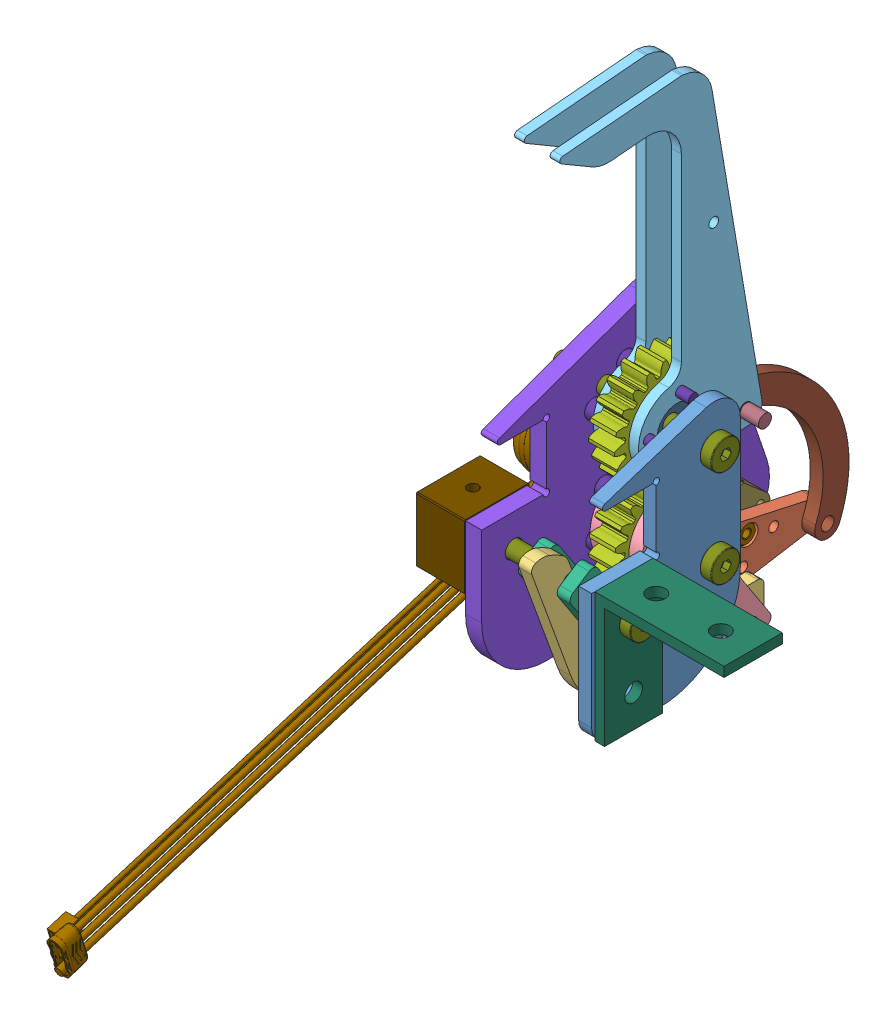
SolidWorks assembly 救援, configuration 默认. Lengths in mm.
Overall size (126.8 267.21 211.07).
35 component instances, 18 part files, 85 mates.
Components (placement in the parent):
- 微动开关固定板6666666-1: 微动开关固定板6666666 [镜像] x (0 0 1) z (0 1 0) size (46 4 73.5)
- 电机摇杆6666666-1: 电机摇杆6666666 [默认] at (-21.5 -25.5 -32) x (0 0.214023 0.976829) z (1 0 0) size (37.41 16.17 4)
- 钩子6666666-1: 钩子6666666 [默认] at (-16.5 -38.9961 -21.8634) x (0 0 -1) z (1 0 0) size (71.95 49.17 4)
- 弯抓6666666-1: 弯抓6666666 [默认] at (-10.5 -5.5 0) x (1 0 0) z (0 -0.837404 -0.546585) size (4 24 57)
- 下爪6666666-1: 下爪6666666 [默认] at (-10.5 24.5 0) x (1 0 0) z (0 0.994276 -0.106844) size (3 72.53 105)
- 摇杆6666666-1: 摇杆6666666 [默认] at (-22.5 -38.9961 6.1366) x (0 -0.837404 -0.546585) z (0 -0.546585 0.837404) size (50 4 10)
- 圆柱齿轮20×1.5-1: 圆柱齿轮20×1.5 [主动] at (-10.5 -5.5 0) x (0 -0.837404 -0.546585) z (-1 0 0) size (32.74 32.74 8)
- 电机固定板6666666-1: 电机固定板6666666 [默认] at (-35 -25.5 -32) x (0 0 1) z (1 0 0) size (89.04 83.8 5)
- RoboMaster M2006 P36直流无刷减速电机-1: RoboMaster M2006 P36直流无刷减速电机 [默认] at (-64.8952 -18.4138 -51.1986) x (0 -0.468644 -0.883387) z (-1 0 0) size (140.17 141.41 64.8)
- 圆柱齿轮20×1.5-3: 圆柱齿轮20×1.5 [从动] at (-10.5 24.5 0) x (0 0.994276 -0.106844) z (-1 0 0) size (32.74 32.74 8)
- 下爪6666666-2: 下爪6666666 [默认] at (-21.5 24.5 0) x (1 0 0) z (0 0.994276 -0.106844) size (3 72.53 105)
- 弯抓6666666-2: 弯抓6666666 [默认] at (-22.5 -5.5 0) x (1 0 0) z (0 -0.837404 -0.546585) size (4 24 57)
- 摇杆6666666-2: 摇杆6666666 [默认] at (-10.5 -38.9961 6.1366) x (0 -0.837404 -0.546585) z (0 -0.546585 0.837404) size (50 4 10)
- 法兰轴承-1: 法兰轴承 [5*11*4-1] at (-9.5 -5.5 0) x (0 -0.083503 0.996508) z (0 -0.996508 -0.083503) size (12.5 4 12.5)
- 法兰轴承-2: 法兰轴承 [5*11*4-1] at (-19.5 -5.5 0) x (0 0.17541 -0.984495) z (0 -0.984495 -0.17541) size (12.5 4 12.5)
- 救援连杆-1: 救援连杆 [默认] at (-14.5 -5.6678 -36.3434) x (0 -0.846057 -0.533093) z (1 0 0) size (65 22.68 4)
- 6mmD型孔联轴器-1: 6mmD型孔联轴器 [默认] at (-21.5 -25.5 -32) x (0 0.95603 0.293268) z (-1 0 0) size (19.05 22 8)
- 一字塞打螺丝-1: 一字塞打螺丝 [￠4*14M4*6] at (-23.5 18.4448 -21.1503) x (0 -0.238327 0.971185) z (-1 0 0) size (8 8 22)
- 法兰轴承-3: 法兰轴承 [5*11*4-1] at (-9.5 24.5 0) x (0 -0.183395 0.983039) z (0 -0.983039 -0.183395) size (12.5 4 12.5)
- 法兰轴承-4: 法兰轴承 [5*11*4-1] at (-19.5 24.5 0) x (0 0.545578 -0.83806) z (0 -0.83806 -0.545578) size (12.5 4 12.5)
- 赛钢轴套-1: 赛钢轴套 [默认] at (-11.5 18.4448 -21.1503) x (0 0.682052 -0.731304) z (1 0 0) size (8 8 2)
- 赛钢轴套-2: 赛钢轴套 [默认] at (-17.5 18.4448 -21.1503) x (0 0.813789 -0.58116) z (1 0 0) size (8 8 2)
- 角件6666666-1: 角件6666666 [默认] at (44 4.5 19) x (0 0 1) z (0 1 0) size (18 40 40)
- 304不锈钢塞打螺钉-1: 304不锈钢塞打螺钉 [5*40*M4] at (10.5 -5.5 28) x (-1 0 0) z (0 -0.996982 0.077638) size (51.5 9 9)
- 304不锈钢塞打螺钉-2: 304不锈钢塞打螺钉 [5*40*M4] at (7.5 24.5 0) x (-1 0 0) z (0 -0.996982 0.077638) size (51.5 9 9)
- 304不锈钢塞打螺钉-3: 304不锈钢塞打螺钉 [5*40*M4] at (7.5 -5.5 0) x (-1 0 0) z (0 -0.996982 0.077638) size (51.5 9 9)
- 12.9级圆柱头螺钉-1: 12.9级圆柱头螺钉 [M3*18] at (-24.5 23.5384 -8.9485) x (0 0.010518 0.999945) z (-1 0 0) size (5.68 5.68 21)
- 12.9级圆柱头螺钉-2: 12.9级圆柱头螺钉 [M3*18] at (-24.5 33.4485 -0.9616) x (0 0.010518 0.999945) z (-1 0 0) size (5.68 5.68 21)
- 12.9级圆柱头螺钉-3: 12.9级圆柱头螺钉 [M3*18] at (-24.5 25.4616 8.9485) x (0 0.010518 0.999945) z (-1 0 0) size (5.68 5.68 21)
- 12.9级圆柱头螺钉-4: 12.9级圆柱头螺钉 [M3*18] at (-24.5 15.5515 0.9616) x (0 0.010518 0.999945) z (-1 0 0) size (5.68 5.68 21)
- 12.9级圆柱头螺钉-5: 12.9级圆柱头螺钉 [M3*20] at (-25.5 -0.5807 -7.5366) x (0 0.010518 0.999945) z (-1 0 0) size (5.68 5.68 23)
- 12.9级圆柱头螺钉-6: 12.9级圆柱头螺钉 [M3*20] at (-25.5 2.0366 4.9193) x (0 0.010518 0.999945) z (-1 0 0) size (5.68 5.68 23)
- 12.9级圆柱头螺钉-7: 12.9级圆柱头螺钉 [M3*20] at (-25.5 -10.4193 7.5366) x (0 0.010518 0.999945) z (-1 0 0) size (5.68 5.68 23)
- 12.9级圆柱头螺钉-8: 12.9级圆柱头螺钉 [M3*20] at (-25.5 -13.0366 -4.9193) x (0 0.010518 0.999945) z (-1 0 0) size (5.68 5.68 23)
- 救援铝件-1: 救援铝件 [默认] at (-42.75 -5.5 28) x (0 0 -1) z (1 0 0) size (20 20 15.5)
Mates (geometry in assembly coordinates):
- 重合1: coincident aligned: plane of 微动开关固定板6666666-1 through (0 0 0) normal (0 1 0)
- 重合2: coincident aligned: plane of 微动开关固定板6666666-1 through (0 0 0) normal (1 0 0)
- 重合3: coincident aligned: plane of 微动开关固定板6666666-1 through (0 0 0) normal (0 0 1)
- 重合4: coincident aligned: plane of 微动开关固定板6666666-1 through (4 4.5 38) normal (0 1 0); plane of 电机固定板6666666-1 through (-30 4.5 18) normal (0 1 0)
- 重合5: coincident aligned: plane of 微动开关固定板6666666-1 through (4 4.5 18) normal (0 0 1); plane of 电机固定板6666666-1 through (-30 24.5 18) normal (0 0 1)
- 同心1: concentric anti-aligned: cylinder of 电机固定板6666666-1 through (-30 -25.5 -32) axis (-1 0 0) radius 7; cylinder of RoboMaster M2006 P36直流无刷减速电机-1 through (-18 -25.5 -32) axis (1 0 0) radius 12.2
- 重合11: coincident anti-aligned: plane of 电机固定板6666666-1 through (-35 -20.5 18) normal (-1 0 0); plane of RoboMaster M2006 P36直流无刷减速电机-1 through (-35 -21.9221 -43.6636) normal (1 0 0)
- 同心4: concentric aligned: cylinder of 微动开关固定板6666666-1 through (4 -5.5 0) axis (-1 0 0) radius 2.5; cylinder of 圆柱齿轮20×1.5-1 through (-10.5 -5.5 0) axis (-1 0 0) radius 5.5
- 重合12: coincident aligned: plane of 圆柱齿轮20×1.5-1 through (-10.5 -5.5 0) normal (1 0 0); plane of 圆柱齿轮20×1.5-3 through (-10.5 24.5 0) normal (1 0 0)
- 同心6: concentric aligned: cylinder of 微动开关固定板6666666-1 through (4 24.5 0) axis (-1 0 0) radius 2.5; cylinder of 下爪6666666-1 through (-7.5 24.5 0) axis (-1 0 0) radius 6.3
- 重合13: coincident anti-aligned: plane of 下爪6666666-1 through (-10.5 24.5 0) normal (-1 0 0); plane of 圆柱齿轮20×1.5-3 through (-10.5 24.5 0) normal (1 0 0)
- 同心8: concentric aligned: cylinder of 下爪6666666-1 through (-7.5 15.5515 0.9616) axis (-1 0 0) radius 1.5; cylinder of 圆柱齿轮20×1.5-3 through (-10.5 15.5515 0.9616) axis (-1 0 0) radius 1.6
- 同心9: concentric aligned: cylinder of 电机固定板6666666-1 through (-30 24.5 0) axis (-1 0 0) radius 2.5; cylinder of 圆柱齿轮20×1.5-3 through (-10.5 24.5 0) axis (-1 0 0) radius 5.5
- 重合14: coincident anti-aligned: plane of 圆柱齿轮20×1.5-3 through (-18.5 19.4635 -13.941) normal (-1 0 0); plane of 下爪6666666-2 through (-18.5 24.5 0) normal (1 0 0)
- 同心10: concentric aligned: cylinder of 微动开关固定板6666666-1 through (4 24.5 0) axis (-1 0 0) radius 2.5; cylinder of 下爪6666666-2 through (-18.5 24.5 0) axis (-1 0 0) radius 6.3
- 同心11: concentric aligned: cylinder of 下爪6666666-1 through (-10.5 18.4448 -21.1503) axis (1 0 0) radius 2; cylinder of 下爪6666666-2 through (-21.5 18.4448 -21.1503) axis (1 0 0) radius 2
- 重合15: coincident anti-aligned: plane of 弯抓6666666-1 through (-10.5 -5.5 0) normal (-1 0 0); plane of 圆柱齿轮20×1.5-1 through (-10.5 -5.5 0) normal (1 0 0)
- 同心12: concentric aligned: cylinder of 弯抓6666666-1 through (-6.5 -5.5 0) axis (-1 0 0) radius 6.3; cylinder of 圆柱齿轮20×1.5-1 through (-10.5 -5.5 0) axis (-1 0 0) radius 5.5
- 重合16: coincident anti-aligned: plane of 圆柱齿轮20×1.5-1 through (-18.5 -10.4243 13.9811) normal (-1 0 0); plane of 弯抓6666666-2 through (-18.5 -5.5 0) normal (1 0 0)
- 同心13: concentric aligned: cylinder of 微动开关固定板6666666-1 through (4 -5.5 0) axis (-1 0 0) radius 2.5; cylinder of 弯抓6666666-2 through (-18.5 -5.5 0) axis (-1 0 0) radius 6.3
- 同心14: concentric aligned: cylinder of 弯抓6666666-1 through (-51.7311 -38.9961 -21.8634) axis (1 0 0) radius 2; cylinder of 弯抓6666666-2 through (-63.7311 -38.9961 -21.8634) axis (1 0 0) radius 2
- 同心15: concentric anti-aligned: cylinder of 摇杆6666666-1 through (-18.5 -5.5 28) axis (-1 0 0) radius 2.525; cylinder of 电机固定板6666666-1 through (-40 -5.5 28) axis (1 0 0) radius 2.75
- 同心16: concentric aligned: cylinder of 微动开关固定板6666666-1 through (4 -5.5 28) axis (-1 0 0) radius 2.75; cylinder of 摇杆6666666-2 through (-6.5 -5.5 28) axis (-1 0 0) radius 2.525
- 同心17: concentric aligned: cylinder of 摇杆6666666-1 through (-18.5 -38.9961 6.1366) axis (-1 0 0) radius 2.525; cylinder of 摇杆6666666-2 through (-6.5 -38.9961 6.1366) axis (-1 0 0) radius 2.525
- 同心18: concentric anti-aligned: cylinder of 钩子6666666-1 through (-12.5 -38.9961 -21.8634) axis (-1 0 0) radius 2; cylinder of 弯抓6666666-2 through (-63.7311 -38.9961 -21.8634) axis (1 0 0) radius 2
- 同心19: concentric aligned: cylinder of 钩子6666666-1 through (-12.5 -38.9961 6.1366) axis (-1 0 0) radius 2; cylinder of 摇杆6666666-1 through (-18.5 -38.9961 6.1366) axis (-1 0 0) radius 2.525
- 重合17: coincident aligned: plane of 摇杆6666666-1 through (-22.5 -38.9961 6.1366) normal (-1 0 0); plane of 弯抓6666666-2 through (-22.5 -5.5 0) normal (-1 0 0)
- 重合18: coincident aligned: plane of 弯抓6666666-1 through (-6.5 -5.5 0) normal (1 0 0); plane of 摇杆6666666-2 through (-6.5 -38.9961 6.1366) normal (1 0 0)
- 宽度2: width aligned: plane of 弯抓6666666-1 through (-6.5 -5.5 0) normal (1 0 0); plane of 弯抓6666666-2 through (-22.5 -5.5 0) normal (-1 0 0); plane of 钩子6666666-1 through (-12.5 -38.9961 -21.8634) normal (1 0 0); plane of 钩子6666666-1 through (-16.5 -38.9961 -21.8634) normal (-1 0 0)
- 同心23: concentric anti-aligned: cylinder of 圆柱齿轮20×1.5-1 through (-10.5 -5.5 0) axis (-1 0 0) radius 5.5; cylinder of 法兰轴承-1 through (-13.5 -5.5 0) axis (1 0 0) radius 2.5
- 重合19: coincident anti-aligned: plane of 圆柱齿轮20×1.5-1 through (-10.5 -5.5 0) normal (1 0 0); plane of 法兰轴承-1 through (-10.5 -5.5 0) normal (-1 0 0)
- 同心24: concentric aligned: cylinder of 圆柱齿轮20×1.5-1 through (-10.5 -5.5 0) axis (-1 0 0) radius 5.5; cylinder of 法兰轴承-2 through (-15.5 -5.5 0) axis (-1 0 0) radius 5.5
- 重合20: coincident anti-aligned: plane of 圆柱齿轮20×1.5-1 through (-18.5 -10.4243 13.9811) normal (-1 0 0); plane of 法兰轴承-2 through (-18.5 -5.5 0) normal (1 0 0)
- 同心25: concentric anti-aligned: cylinder of 下爪6666666-2 through (-21.5 18.4448 -21.1503) axis (1 0 0) radius 2; cylinder of 救援连杆-1 through (-12.5 18.4448 -21.1503) axis (-1 0 0) radius 2
- 宽度3: width aligned: plane of 下爪6666666-1 through (-7.5 24.5 0) normal (1 0 0); plane of 下爪6666666-2 through (-21.5 24.5 0) normal (-1 0 0); plane of 救援连杆-1 through (-12.5 0.9732 -20.1525) normal (1 0 0); plane of 救援连杆-1 through (-16.5 0.9732 -20.1525) normal (-1 0 0)
- 同心26: concentric aligned: cylinder of 电机摇杆6666666-1 through (-17.5 -29.7805 -51.5366) axis (-1 0 0) radius 2; cylinder of 救援连杆-1 through (-12.5 -29.7805 -51.5366) axis (-1 0 0) radius 2
- 同心27: concentric aligned: cylinder of 弯抓6666666-1 through (-6.5 -10.4193 7.5366) axis (-1 0 0) radius 1.5; cylinder of 圆柱齿轮20×1.5-1 through (-10.5 -10.4193 7.5366) axis (-1 0 0) radius 1.6
- 齿轮配合1: gear = 20 : 20 mm: cylinder of 圆柱齿轮20×1.5-1 through (-20.5 -5.5 0) axis (1 0 0) radius 16.5; cylinder of 圆柱齿轮20×1.5-3 through (-20.5 24.5 0) axis (1 0 0) radius 16.5
- 同心28: concentric anti-aligned: cylinder of 电机摇杆6666666-1 through (-17.5 -25.5 -32) axis (-1 0 0) radius 3; cylinder of RoboMaster M2006 P36直流无刷减速电机-1 through (-18 -25.5 -32) axis (1 0 0) radius 3
- 同心29: concentric aligned: cylinder of RoboMaster M2006 P36直流无刷减速电机-1 through (-18 -25.5 -32) axis (1 0 0) radius 3; cylinder of 6mmD型孔联轴器-1 through (-29.5 -25.5 -32) axis (1 0 0) radius 3
- 平行1: parallel anti-aligned: plane of RoboMaster M2006 P36直流无刷减速电机-1 through (-18 -19.9867 -32.9237) normal (0 0.293268 -0.95603); plane of 6mmD型孔联轴器-1 through (-29.5 -26.3522 -34.8764) normal (0 -0.293268 0.95603)
- 重合22: coincident anti-aligned: plane of 电机摇杆6666666-1 through (-21.5 -22.2943 -22.0411) normal (-1 0 0); plane of 6mmD型孔联轴器-1 through (-21.5 -27.8461 -24.3518) normal (1 0 0)
- 同心31: concentric anti-aligned: cylinder of 圆柱齿轮20×1.5-3 through (-10.5 24.5 0) axis (-1 0 0) radius 5.5; cylinder of 法兰轴承-3 through (-13.5 24.5 0) axis (1 0 0) radius 5.5
- 重合24: coincident anti-aligned: plane of 圆柱齿轮20×1.5-3 through (-10.5 24.5 0) normal (1 0 0); plane of 法兰轴承-3 through (-10.5 24.5 0) normal (-1 0 0)
- 同心32: concentric aligned: cylinder of 圆柱齿轮20×1.5-3 through (-10.5 24.5 0) axis (-1 0 0) radius 5.5; cylinder of 法兰轴承-4 through (-15.5 24.5 0) axis (-1 0 0) radius 5.5
- 重合25: coincident anti-aligned: plane of 圆柱齿轮20×1.5-3 through (-18.5 19.4635 -13.941) normal (-1 0 0); plane of 法兰轴承-4 through (-18.5 24.5 0) normal (1 0 0)
- 重合26: coincident anti-aligned: plane of 救援连杆-1 through (-12.5 0.9732 -20.1525) normal (1 0 0); plane of 赛钢轴套-1 through (-12.5 18.4448 -21.1503) normal (-1 0 0)
- 重合27: coincident anti-aligned: plane of 下爪6666666-2 through (-18.5 24.5 0) normal (1 0 0); plane of 赛钢轴套-2 through (-18.5 18.4448 -21.1503) normal (-1 0 0)
- 同心343: concentric aligned: cylinder of 下爪6666666-2 through (-21.5 18.4448 -21.1503) axis (1 0 0) radius 2; cylinder of 一字塞打螺丝-1 through (-1.5 18.4448 -21.1503) axis (1 0 0) radius 2
- 同心344: concentric anti-aligned: cylinder of 下爪6666666-2 through (-21.5 18.4448 -21.1503) axis (1 0 0) radius 2; cylinder of 赛钢轴套-1 through (-10.5 18.4448 -21.1503) axis (-1 0 0) radius 4
- 同心345: concentric aligned: cylinder of 下爪6666666-2 through (-21.5 18.4448 -21.1503) axis (1 0 0) radius 2; cylinder of 一字塞打螺丝-1 through (-1.5 18.4448 -21.1503) axis (1 0 0) radius 4
- 重合34: coincident anti-aligned: plane of 下爪6666666-2 through (-21.5 24.5 0) normal (-1 0 0); plane of 一字塞打螺丝-1 through (-21.5 22.3295 -20.197) normal (1 0 0)
- 距离4: distance = 1 mm anti-aligned: plane of 电机摇杆6666666-1 through (-17.5 -22.2943 -22.0411) normal (1 0 0); plane of 救援连杆-1 through (-16.5 0.9732 -20.1525) normal (-1 0 0)
- 同心346: concentric anti-aligned: cylinder of 一字塞打螺丝-1 through (-1.5 18.4448 -21.1503) axis (1 0 0) radius 2; cylinder of 赛钢轴套-2 through (-16.5 18.4448 -21.1503) axis (-1 0 0) radius 4
- 重合35: coincident anti-aligned: plane of RoboMaster M2006 P36直流无刷减速电机-1 through (-29.5 -19.84 -33.4017) normal (1 0 0); plane of 6mmD型孔联轴器-1 through (-29.5 -25.5 -32) normal (-1 0 0)
- 重合36: coincident anti-aligned: plane of 微动开关固定板6666666-1 through (4 -31.5 33) normal (1 0 0); plane of 角件6666666-1 through (4 4.5 37) normal (-1 0 0)
- 同心347: concentric aligned: cylinder of 微动开关固定板6666666-1 through (4 -25.5 28) axis (-1 0 0) radius 2.75; cylinder of 角件6666666-1 through (44 -25.5 28) axis (-1 0 0) radius 2.75
- 平行2: parallel aligned: plane of 微动开关固定板6666666-1 through (4 4.5 38) normal (0 0 1); plane of 角件6666666-1 through (44 4.5 37) normal (0 0 1)
- 距离5: distance = 30 mm anti-aligned: plane of 微动开关固定板6666666-1 through (0 -31.5 33) normal (-1 0 0); plane of 电机固定板6666666-1 through (-30 -20.5 18) normal (1 0 0)
- 同心348: concentric aligned: cylinder of 角件6666666-1 through (44 -5.5 28) axis (-1 0 0) radius 2.75; cylinder of 304不锈钢塞打螺钉-1 through (-41 -5.5 28) axis (-1 0 0) radius 2.5
- 重合37: coincident anti-aligned: plane of 角件6666666-1 through (7 -35.5 37) normal (1 0 0); plane of 304不锈钢塞打螺钉-1 through (7 -5.8494 23.5136) normal (-1 0 0)
- 同心349: concentric aligned: cylinder of 微动开关固定板6666666-1 through (4 24.5 0) axis (-1 0 0) radius 2.5; cylinder of 304不锈钢塞打螺钉-2 through (-44 24.5 0) axis (-1 0 0) radius 2.5
- 重合38: coincident anti-aligned: plane of 微动开关固定板6666666-1 through (4 -31.5 33) normal (1 0 0); plane of 304不锈钢塞打螺钉-2 through (4 24.1506 -4.4864) normal (-1 0 0)
- 同心350: concentric aligned: cylinder of 微动开关固定板6666666-1 through (4 -5.5 0) axis (-1 0 0) radius 2.5; cylinder of 304不锈钢塞打螺钉-3 through (-44 -5.5 0) axis (-1 0 0) radius 2.5
- 重合39: coincident anti-aligned: plane of 微动开关固定板6666666-1 through (4 -31.5 33) normal (1 0 0); plane of 304不锈钢塞打螺钉-3 through (4 -5.8494 -4.4864) normal (-1 0 0)
- 同心351: concentric anti-aligned: cylinder of 下爪6666666-2 through (-18.5 23.5384 -8.9485) axis (-1 0 0) radius 1.5; cylinder of 12.9级圆柱头螺钉-1 through (-3.5 23.5384 -8.9485) axis (1 0 0) radius 1.5
- 重合40: coincident anti-aligned: plane of 下爪6666666-2 through (-21.5 24.5 0) normal (-1 0 0); plane of 12.9级圆柱头螺钉-1 through (-21.5 26.3782 -8.9784) normal (1 0 0)
- 同心3521: concentric anti-aligned: cylinder of 下爪6666666-2 through (-18.5 33.4485 -0.9616) axis (-1 0 0) radius 1.5; cylinder of 12.9级圆柱头螺钉-2 through (-3.5 33.4485 -0.9616) axis (1 0 0) radius 2.84
- 重合411: coincident anti-aligned: plane of 下爪6666666-2 through (-21.5 24.5 0) normal (-1 0 0); plane of 12.9级圆柱头螺钉-2 through (-21.5 36.2883 -0.9915) normal (1 0 0)
- 同心3531: concentric anti-aligned: cylinder of 下爪6666666-2 through (-18.5 25.4616 8.9485) axis (-1 0 0) radius 1.5; cylinder of 12.9级圆柱头螺钉-3 through (-3.5 25.4616 8.9485) axis (1 0 0) radius 2.84
- 重合421: coincident anti-aligned: plane of 下爪6666666-2 through (-21.5 24.5 0) normal (-1 0 0); plane of 12.9级圆柱头螺钉-3 through (-21.5 28.3014 8.9186) normal (1 0 0)
- 同心3541: concentric anti-aligned: cylinder of 下爪6666666-2 through (-18.5 15.5515 0.9616) axis (-1 0 0) radius 1.5; cylinder of 12.9级圆柱头螺钉-4 through (-3.5 15.5515 0.9616) axis (1 0 0) radius 2.84
- 重合431: coincident anti-aligned: plane of 下爪6666666-2 through (-21.5 24.5 0) normal (-1 0 0); plane of 12.9级圆柱头螺钉-4 through (-21.5 18.3914 0.9317) normal (1 0 0)
- 同心3551: concentric anti-aligned: cylinder of 弯抓6666666-2 through (-18.5 -0.5807 -7.5366) axis (-1 0 0) radius 1.5; cylinder of 12.9级圆柱头螺钉-5 through (-2.5 -0.5807 -7.5366) axis (1 0 0) radius 2.84
- 重合441: coincident anti-aligned: plane of 弯抓6666666-2 through (-22.5 -5.5 0) normal (-1 0 0); plane of 12.9级圆柱头螺钉-5 through (-22.5 2.2591 -7.5665) normal (1 0 0)
- 同心3561: concentric anti-aligned: cylinder of 弯抓6666666-2 through (-18.5 2.0366 4.9193) axis (-1 0 0) radius 1.5; cylinder of 12.9级圆柱头螺钉-6 through (-2.5 2.0366 4.9193) axis (1 0 0) radius 2.84
- 重合451: coincident anti-aligned: plane of 弯抓6666666-2 through (-22.5 -5.5 0) normal (-1 0 0); plane of 12.9级圆柱头螺钉-6 through (-22.5 4.8765 4.8894) normal (1 0 0)
- 同心3571: concentric anti-aligned: cylinder of 弯抓6666666-2 through (-18.5 -10.4193 7.5366) axis (-1 0 0) radius 1.5; cylinder of 12.9级圆柱头螺钉-7 through (-2.5 -10.4193 7.5366) axis (1 0 0) radius 2.84
- 重合461: coincident anti-aligned: plane of 弯抓6666666-2 through (-22.5 -5.5 0) normal (-1 0 0); plane of 12.9级圆柱头螺钉-7 through (-22.5 -7.5794 7.5068) normal (1 0 0)
- 同心3581: concentric anti-aligned: cylinder of 弯抓6666666-2 through (-18.5 -13.0366 -4.9193) axis (-1 0 0) radius 1.5; cylinder of 12.9级圆柱头螺钉-8 through (-2.5 -13.0366 -4.9193) axis (1 0 0) radius 2.84
- 重合471: coincident anti-aligned: plane of 弯抓6666666-2 through (-22.5 -5.5 0) normal (-1 0 0); plane of 12.9级圆柱头螺钉-8 through (-22.5 -10.1968 -4.9491) normal (1 0 0)
- 同心3582: concentric anti-aligned: cylinder of 304不锈钢塞打螺钉-1 through (-41 -5.5 28) axis (-1 0 0) radius 2; cylinder of 救援铝件-1 through (-35 -5.5 28) axis (1 0 0) radius 1.65
- 重合472: coincident anti-aligned: plane of 电机固定板6666666-1 through (-35 -20.5 18) normal (-1 0 0); plane of 救援铝件-1 through (-35 -5.5 28) normal (1 0 0)
- 平行3: parallel aligned: plane of 电机固定板6666666-1 through (-30 4.5 18) normal (0 1 0); plane of 救援铝件-1 through (-35 4.5 38) normal (0 1 0)
- LimitAngle1: limit planar angle = 1.570796 rad anti-aligned: plane of 角件6666666-1 through (44 4.5 37) normal (0 1 0); plane of 下爪6666666-2 through (-28.5 24.5 -1.2821) normal (0 0 1)
